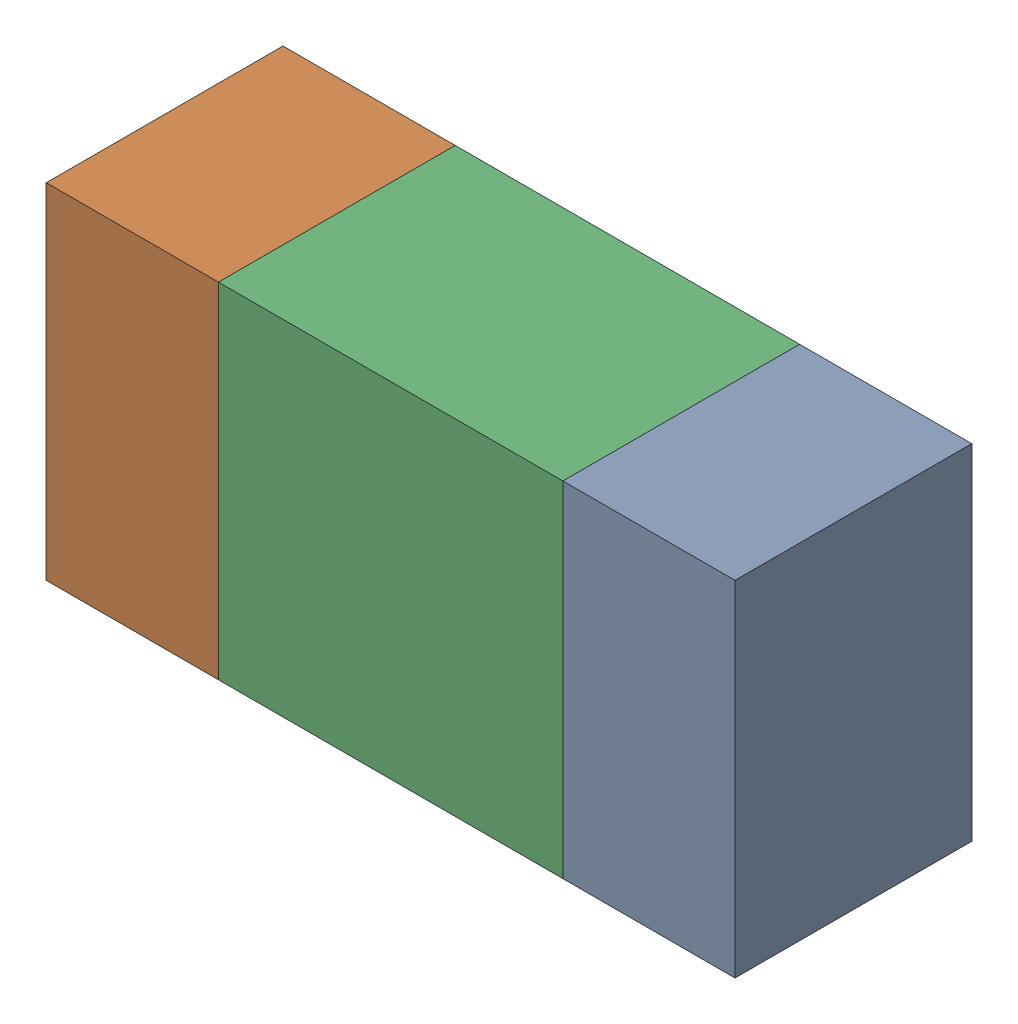
SolidWorks assembly R35, configuration ﾃﾞﾌｫﾙﾄ. Lengths in mm.
Overall size (1.6 0.8 0.55).
6 component instances, 2 part files, 0 mates.
Components (placement in the parent):
- 689261512-1: 689261512 [ﾃﾞﾌｫﾙﾄ] at (11.3949 15.5576 -1.7503) size (0.4 0.8 0.55)
  - Extruded_32-1: Extruded_32 [ﾃﾞﾌｫﾙﾄ] at origin size (0.4 0.8 0.55)
- 689261512-2: 689261512 [ﾃﾞﾌｫﾙﾄ] at (10.1949 15.5576 -1.7503) size (0.4 0.8 0.55)
  - Extruded_32-1: Extruded_32 [ﾃﾞﾌｫﾙﾄ] at origin size (0.4 0.8 0.55)
- 689261648-1: 689261648 [ﾃﾞﾌｫﾙﾄ] at (10.795 15.5576 -1.7503) size (0.8 0.8 0.55)
  - Extruded_33-1: Extruded_33 [ﾃﾞﾌｫﾙﾄ] at origin size (0.8 0.8 0.55)
